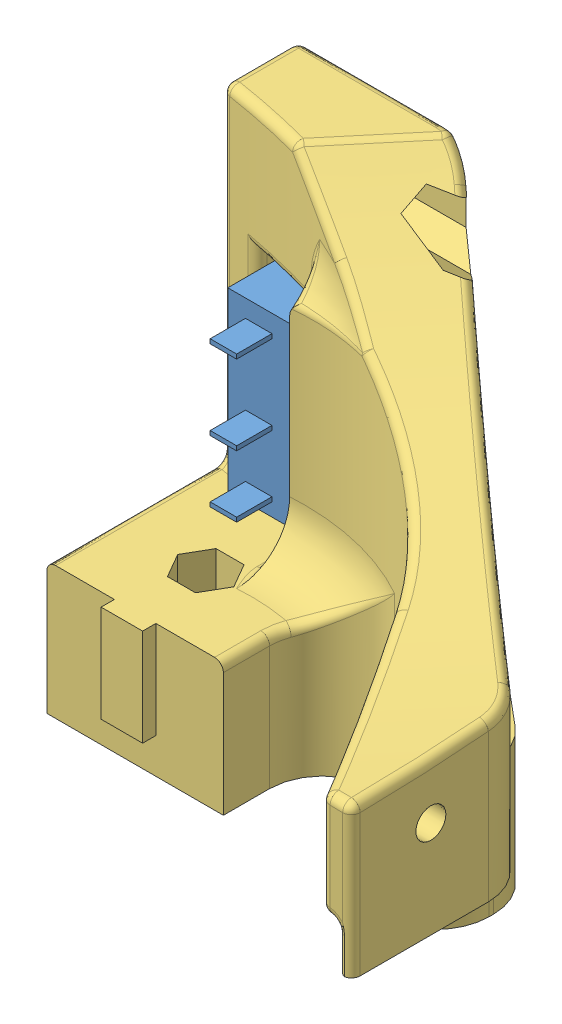
SolidWorks assembly _Symétrie_Angle, configuration Défaut. Lengths in mm.
Overall size (53.5 52 51.1).
4 component instances, 3 part files, 3 mates.
Components (placement in the parent):
- _Symétrie_microswitchGaletAss-1: _Symétrie_microswitchGaletAss [Défaut] at (85.155 44 -75) x (0 -1 0) z (1 0 0) size (21.06 21.1 7)
  - _Symétrie_microswitchGalet02-1: _Symétrie_microswitchGalet02 [Défaut] at origin size (20 15 7)
  - _Symétrie_microswitchGalet01-1: _Symétrie_microswitchGalet01 [Défaut] at (1.7099 12.1145 0) x (0.996636 -0.081957 0) z (0 0 1) size (19 9 6)
- _Symétrie_Angle_support-1: _Symétrie_Angle_support [Défaut] at (86.155 7 -50) size (53.5 52 49)
Mates (geometry in assembly coordinates):
- Coïncidente1: coincident: plane of assembly; plane of assembly; plane of _Symétrie_microswitchGaletAss-1/_Symétrie_microswitchGalet02-1 through (88.655 44 -75) normal (1 0 0); plane of _Symétrie_Angle_support-1 through (88.655 7 -50) normal (-1 0 0)
- Coaxiale1: concentric: cylinder of assembly; cylinder of assembly; cylinder of _Symétrie_microswitchGaletAss-1/_Symétrie_microswitchGalet02-1 through (81.655 38.5 -78) axis (1 0 0) radius 1; cylinder of _Symétrie_Angle_support-1 through (129.655 38.5 -78) axis (-1 0 0) radius 1.5
- Coaxiale2: concentric: cylinder of assembly; cylinder of assembly; cylinder of _Symétrie_microswitchGaletAss-1/_Symétrie_microswitchGalet02-1 through (81.655 29.5 -78) axis (1 0 0) radius 1; cylinder of _Symétrie_Angle_support-1 through (129.655 29.5 -78) axis (-1 0 0) radius 1.5
